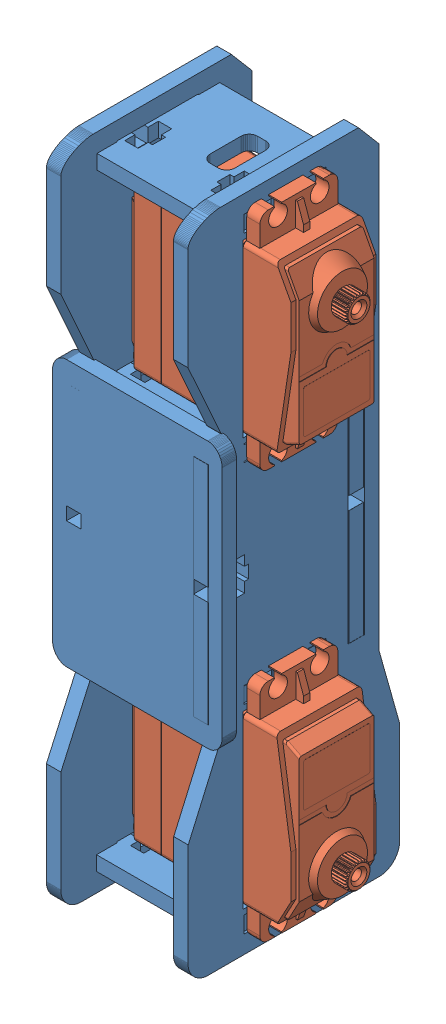
SolidWorks assembly left_shin, configuration Default. Lengths in mm.
Overall size (55.56 159.23 51.17).
3 component instances, 2 part files, 2 mates.
Components (placement in the parent):
- left_shin_100-1: left_shin_100 [Default] at (-17.4627 -1.9908 116.5173) size (40.95 159.23 51.17)
- SW2019 DS3225MG Servo 25Kg 4.8-6.8V-1: SW2019 DS3225MG Servo 25Kg 4.8-6.8V [Default] at (66.0792 136.4237 143.42) x (0 -1 0) z (0.999983 0 0.005769) size (54.3 20.4 45.91)
- SW2019 DS3225MG Servo 25Kg 4.8-6.8V-2: SW2019 DS3225MG Servo 25Kg 4.8-6.8V [Default] at (66.0902 17.8483 143.4392) x (0 1 0) z (0.999976 0 0.006862) size (54.3 20.4 45.91)
Mates (geometry in assembly coordinates):
- Coincident1: coincident anti-aligned: line of left_shin_100-1 through (48.2207 147.0753 153.5171) axis (0 -1 0); line of SW2019 DS3225MG Servo 25Kg 4.8-6.8V-1 through (48.2207 107.3237 153.5171) axis (0 1 0)
- Coincident2: coincident anti-aligned: line of left_shin_100-1 through (48.2207 48.4856 153.5168) axis (0 -1 0); line of SW2019 DS3225MG Servo 25Kg 4.8-6.8V-2 through (48.2207 8.7483 153.5168) axis (0 1 0)
